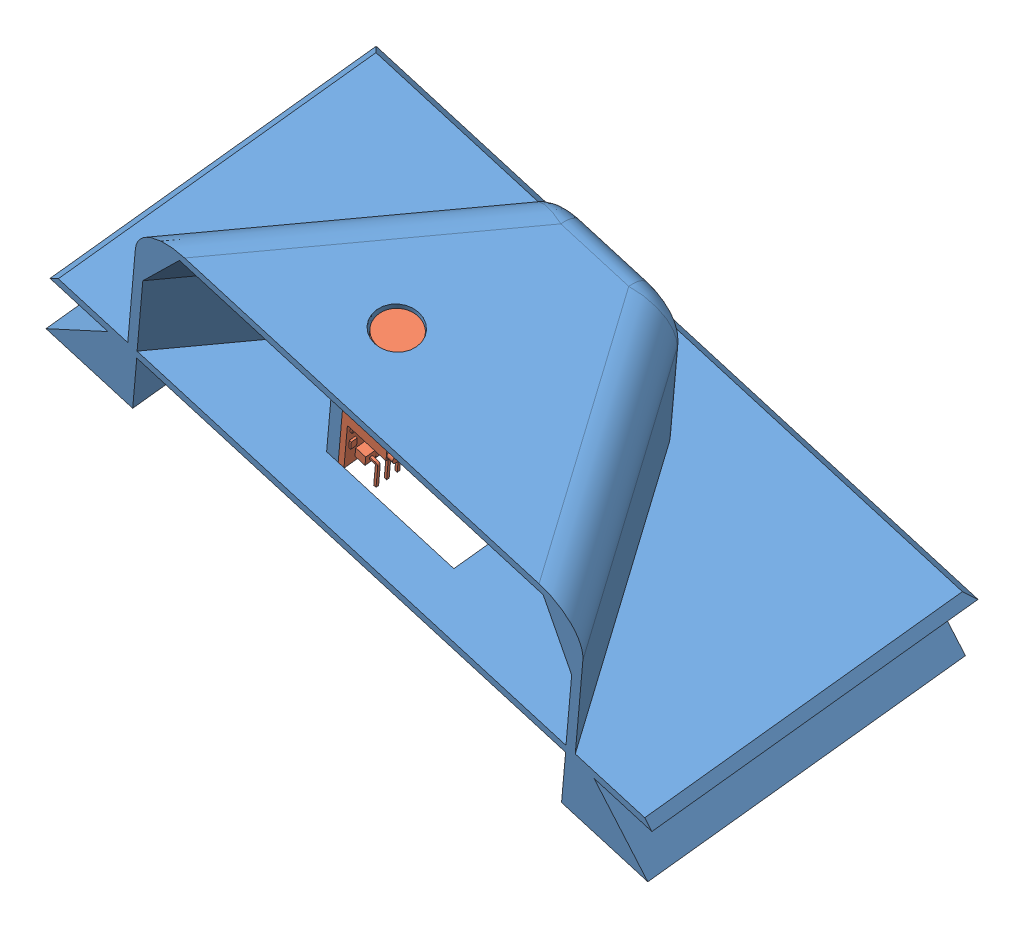
SolidWorks assembly Hood + Mic + Cam, configuration Default. Lengths in mm.
Overall size (169.56 108.37 88.06).
2 component instances, 2 part files, 3 mates.
Components (placement in the parent):
- Hood-1: Hood [Default] at (-14.8648 52.7531 172.1044) x (-0.962772 0.270071 -0.0115) z (-0.063713 -0.185376 0.9806) size (156.01 55 77)
- Mic.step-1: Mic.step [Default] at (32.6504 62.9288 158.5467) x (-0.2627 -0.944827 -0.195682) z (-0.063713 -0.185376 0.9806) size (41.3 13.35 15.1)
Mates (geometry in assembly coordinates):
- Coincident16: coincident: plane of Hood-1 through (34.1559 79.8721 169.5469) normal (-0.063713 -0.185376 0.9806); plane of Mic.step-1 through (38.2371 77.753 169.4115) normal (-0.063713 -0.185376 0.9806)
- Coincident17: coincident: line of Hood-1 through (37.0442 79.0619 169.5814) axis (-0.2627 -0.944827 -0.195682); line of Mic.step-1 through (36.7929 78.1582 169.3942) axis (-0.2627 -0.944827 -0.195682)
- Concentric2: concentric anti-aligned: cylinder of Hood-1 through (20.7504 57.4568 156.739) axis (0.962772 -0.270071 0.0115) radius 2.1; circle of Mic.step-1
